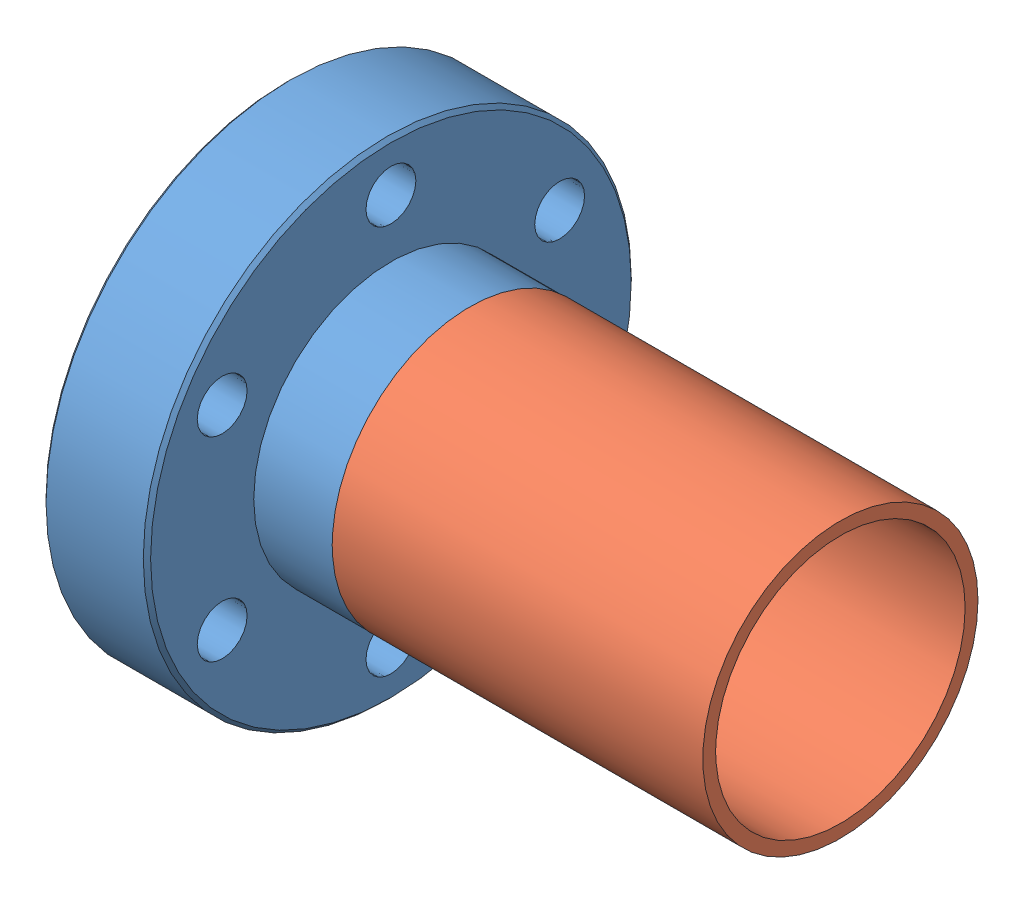
SolidWorks assembly 401021, configuration Default. Lengths in mm.
Overall size (38.35 33.78 33.78).
2 component instances, 2 part files, 2 mates.
Components (placement in the parent):
- 130004-1: 130004 [Default] at (9.3487 21.131 21.5195) size (14.22 33.78 33.78)
- 940100-1: 940100 [Default] at (47.7027 21.131 21.5195) x (0 0 1) z (-1 0 0) size (19.05 19.05 25.65)
Mates (geometry in assembly coordinates):
- Concentric1: concentric anti-aligned: cylinder of 130004-1 through (9.3487 21.131 21.5195) axis (-1 0 0) radius 7.9375; cylinder of 940100-1 through (22.0487 21.131 21.5195) axis (1 0 0) radius 9.525
- Coincident1: coincident anti-aligned: plane of 130004-1 through (22.0487 29.64 21.5195) normal (1 0 0); plane of 940100-1 through (22.0487 21.131 21.5195) normal (-1 0 0)
